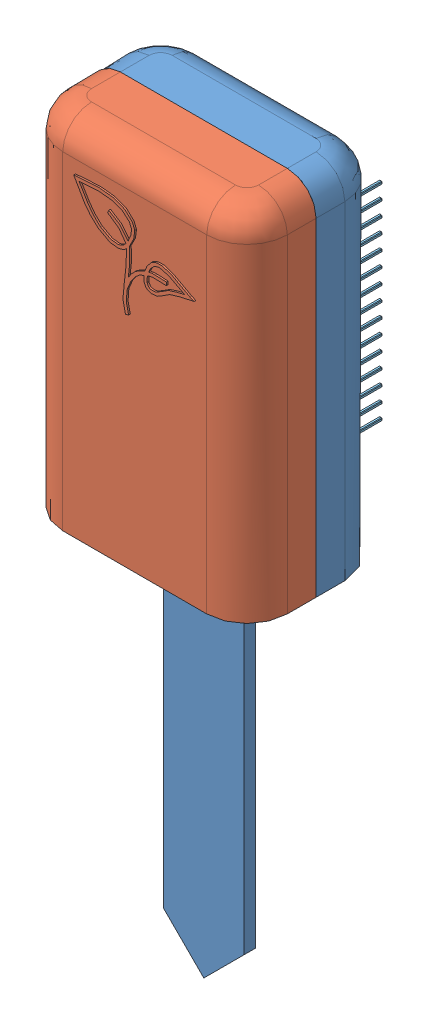
SolidWorks assembly assembly, configuration Default. Lengths in mm.
Overall size (39 129 30.3).
8 component instances, 6 part files, 8 mates.
Components (placement in the parent):
- enclosure base-3: enclosure base [Default] at (-102.8314 85.962 -17.0884) x (1 0 0) z (0 1 0) size (39 14 129)
- enclosure front-2: enclosure front [Default] at (-102.8314 85.962 2.9116) x (-1 0 0) z (0 1 0) size (39 12.3 62)
- ESP-WROOM32-1: ESP-WROOM32 [Default] at (-101.2955 101.227 -14.292) x (1 0 0) z (0 -1 0) size (28.5 12.4 50.93)
  - ESP-WROOM32.STEP-1: ESP-WROOM32.STEP [Default] at origin size (28.5 12.4 50.93)
    - micro_usb_47346-0001.STEP-1: micro_usb_47346-0001.STEP [Default] at (-1.7662 -0.0714 7.915) size (7.98 2.94 5.43)
    - ESP-WROOM-32.STEP-1: ESP-WROOM-32.STEP [Default] at (-1.5465 -1.4314 -27.485) x (-1 0 0) z (0 1 0) size (18.07 25.54 3.04)
    - 6.ESP-32_Predeterminado.STEP-1: 6.ESP-32_Predeterminado.STEP [Default] at (-1.5465 -2.7964 -14.985) size (28.5 11.4 50.5)
- battery-1: battery [Default] at (-102.8314 115.962 -7.0884) size (25 40 8)
Mates (geometry in assembly coordinates):
- Coincident3: coincident aligned: line of enclosure base-3 through (-122.3314 142.962 -7.0884) axis (0 -1 0); line of enclosure front-2 through (-122.3314 142.962 -7.0884) axis (0 -1 0)
- Coincident4: coincident anti-aligned: line of enclosure base-3 through (-93.8314 85.962 -7.0884) axis (1 0 0); line of enclosure front-2 through (-83.3314 85.962 -7.0884) axis (-1 0 0)
- Coincident5: coincident anti-aligned: plane of enclosure base-3 through (-115.3314 145.962 -17.0884) normal (0 0 1); plane of ESP-WROOM32-1/ESP-WROOM32.STEP-1/6.ESP-32_Predeterminado.STEP-1 through (-102.842 116.212 -17.0884) normal (0 0 -1)
- Distance2: distance = 3 mm anti-aligned: plane of ESP-WROOM32-1/ESP-WROOM32.STEP-1/6.ESP-32_Predeterminado.STEP-1 through (-102.842 90.962 -15.5884) normal (0 -1 0); plane of enclosure base-3 through (-90.3314 87.962 -12.0884) normal (0 1 0)
- Distance3: distance = 3.2605 mm: plane of enclosure base-3 through (-85.3314 145.962 -12.0884) normal (-1 0 0); line of ESP-WROOM32-1/ESP-WROOM32.STEP-1/6.ESP-32_Predeterminado.STEP-1 through (-88.592 91.962 -15.5884) axis (0 1 0)
- Distance4: distance = 2 mm anti-aligned: plane of enclosure front-2 through (-90.3314 145.962 2.9116) normal (0 0 -1); plane of battery-1 through (-102.8314 115.962 0.9116) normal (0 0 1)
- Distance5: distance = 5 mm anti-aligned: plane of enclosure front-2 through (-120.3314 145.962 -2.0884) normal (1 0 0); plane of battery-1 through (-115.3314 95.962 0.9116) normal (-1 0 0)
- Distance6: distance = 10 mm anti-aligned: plane of enclosure front-2 through (-90.3314 145.962 -2.0884) normal (0 -1 0); plane of battery-1 through (-115.3314 135.962 0.9116) normal (0 1 0)
